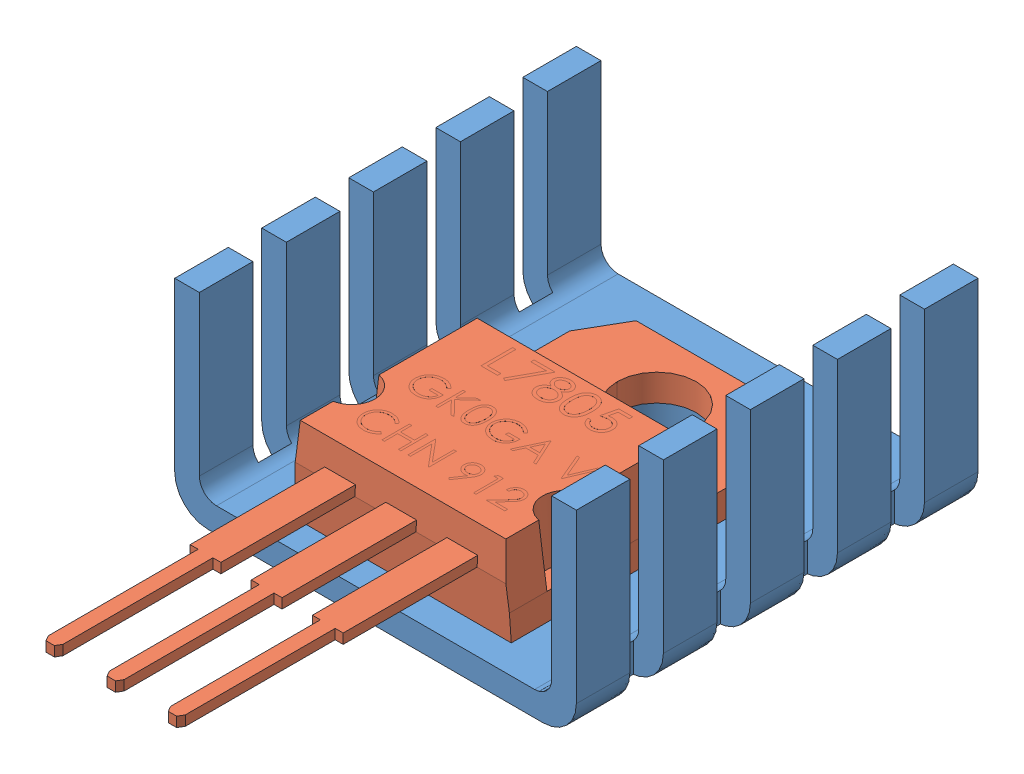
SolidWorks assembly 7805, configuration Varsayılan. Lengths in mm.
Overall size (19.05 9.53 31.58).
3 component instances, 2 part files, 0 mates.
Components (placement in the parent):
- 7805.STEP-1: 7805.STEP [Varsayılan] at origin size (19.05 9.53 31.58)
  - TO220_Heatsink.STEP-1: TO220_Heatsink.STEP [Varsayılan] at (-10.3221 -3.2724 28.5597) size (19.05 9.53 19.05)
  - L7805.STEP-1: L7805.STEP [Varsayılan] at (-0.7971 -2.104 15.2247) x (1 0 0) z (0 1 0) size (10.16 28.82 4.2)
